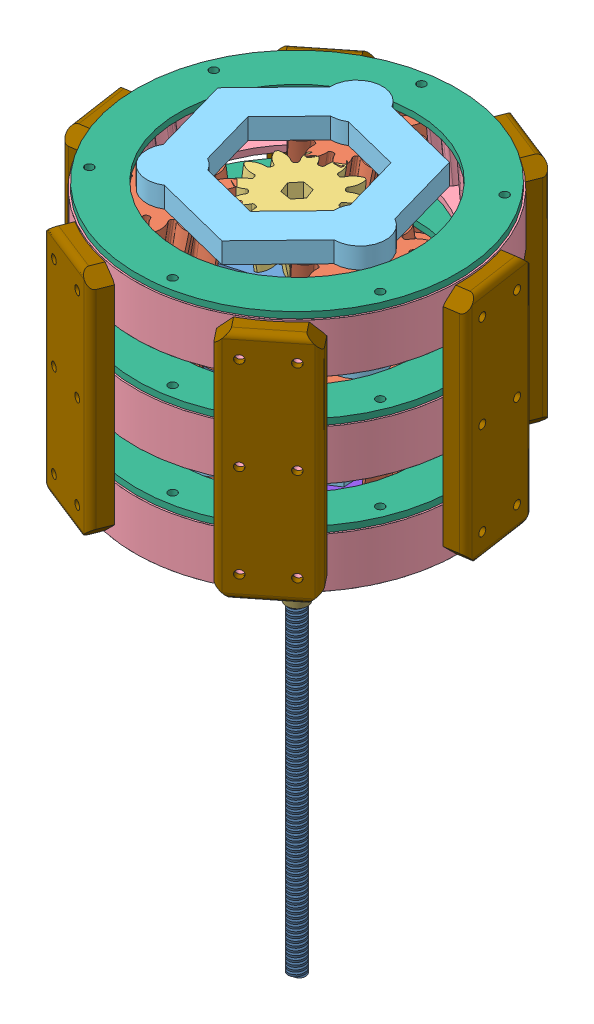
SolidWorks assembly beast_of_burden_REV01, configuration Default. Lengths in mm.
Overall size (217.77 339.35 217.77).
35 component instances, 12 part files, 99 mates.
Components (placement in the parent):
- Planet Carrier REV01-1: Planet Carrier REV01 [Default] at (53.0057 38.5104 215.4418) x (-0.244103 0 0.969749) z (0 1 0) size (94.36 84.54 31)
- planet_helical-1: planet_helical [Default] at (94.0814 53.5104 225.7812) x (-0.940132 0 -0.34081) z (0.34081 0 -0.940132) size (48.42 20.01 48.73)
- sun_helical-1: sun_helical [Default] at (53.0057 53.5104 215.4418) x (-0.935386 0 0.353629) z (-0.353629 0 -0.935386) size (48.42 20.01 48.73)
- planet_helical-2: planet_helical [Default] at (41.4221 53.5104 174.6994) x (-0.765305 0 0.643668) z (-0.643668 0 -0.765305) size (48.42 20.01 48.73)
- planet_helical-3: planet_helical [Default] at (23.5136 53.5104 245.8446) x (0.175396 0 0.984498) z (-0.984498 0 0.175396) size (48.42 20.01 48.73)
- ring_helical-1: ring_helical [Default] at (53.0057 54.0104 215.4418) x (0.989106 0 -0.147208) z (0.147208 0 0.989106) size (166.59 24 159.27)
- Planet Cap REV01-1: Planet Cap REV01 [Default] at (52.6138 69.5104 215.3431) x (-0.717776 0 -0.696274) z (0 1 0) size (98.36 107.21 19)
- ring_helical_cap-1: ring_helical_cap [Default] at (53.0057 64.5104 215.4418) x (0.989106 0 -0.147208) z (0.147208 0 0.989106) size (155 3 155)
- Hand Crank Key REV01-2: Hand Crank Key REV01 [Default] at (53.0057 18.5104 215.4418) x (0.717776 0 0.696274) z (0.696274 0 -0.717776) size (18.48 27 16)
- sun_helical-2: sun_helical [Default] at (53.0057 8.5104 215.4418) x (-0.969749 0 -0.244103) z (0.244103 0 -0.969749) size (48.42 20.01 48.73)
- Planet Carrier REV01-2: Planet Carrier REV01 [Default] at (53.0057 -6.4896 215.4418) x (-0.696169 0 -0.717878) z (0 1 0) size (94.36 84.54 31)
- planet_helical-4: planet_helical [Default] at (42.6723 8.5104 174.3646) x (0.408652 0 0.91269) z (-0.91269 0 0.408652) size (48.42 20.01 48.73)
- planet_helical-5: planet_helical [Default] at (22.5986 8.5104 244.9294) x (0.811958 0 0.583716) z (-0.583716 0 0.811958) size (48.42 20.01 48.73)
- planet_helical-6: planet_helical [Default] at (93.7463 8.5104 227.0313) x (0.41289 0 0.910781) z (-0.910781 0 0.41289) size (48.42 20.01 48.73)
- Planet Cap REV01-2: Planet Cap REV01 [Default] at (53.0057 24.5104 215.4418) x (0.969785 0 -0.243961) z (0 1 0) size (98.36 107.21 19)
- ring_helical-2: ring_helical [Default] at (53.0057 9.0104 215.4418) x (-0.989106 0 0.147208) z (-0.147208 0 -0.989106) size (166.59 24 159.27)
- ring_helical_cap-2: ring_helical_cap [Default] at (53.0057 19.5104 215.4418) x (-0.989106 0 0.147208) z (-0.147208 0 -0.989106) size (155 3 155)
- Hand Crank Key REV01-3: Hand Crank Key REV01 [Default] at (53.0057 -26.4896 215.4418) x (-0.696169 0 -0.717878) z (-0.717878 0 0.696169) size (18.48 27 16)
- sun_helical-3: sun_helical [Default] at (53.0057 -36.4896 215.4418) x (0.243961 0 0.969785) z (-0.969785 0 0.243961) size (48.42 20.01 48.73)
- Planet Cap REV01-3: Planet Cap REV01 [Default] at (53.0057 -20.4896 215.4418) x (0.457092 0 -0.88942) z (0 1 0) size (98.36 107.21 19)
- planet_helical-7: planet_helical [Default] at (88.6095 -36.4896 192.4964) x (0.219463 0 0.975621) z (-0.975621 0 0.219463) size (48.42 20.01 48.73)
- planet_helical-8: planet_helical [Default] at (55.0751 -36.4896 257.7482) x (0.223022 0 0.974813) z (-0.974813 0 0.223022) size (48.42 20.01 48.73)
- planet_helical-9: planet_helical [Default] at (15.3326 -36.4896 196.0807) x (0.675249 0 0.737589) z (-0.737589 0 0.675249) size (48.42 20.01 48.73)
- ring_helical-3: ring_helical [Default] at (53.0057 -35.9896 215.4418) x (0.989106 0 -0.147208) z (0.147208 0 0.989106) size (166.59 24 159.27)
- ring_helical_cap-3: ring_helical_cap [Default] at (53.0057 -25.4896 215.4418) x (0.622038 0 0.782987) z (-0.782987 0 0.622038) size (155 3 155)
- carrier_end_effector_REV01-1: carrier_end_effector_REV01 [Default] at (53.0057 -51.4896 215.4418) x (-0.998806 0 0.048857) z (0 1 0) size (94.36 84.54 41)
- gearbox_spline_REV01-3: gearbox_spline_REV01 [Default] at (53.006 7.5104 215.4422) x (0.622038 0 0.782987) z (-0.782987 0 0.622038) size (10 112.5 38)
- gearbox_spline_REV01-4: gearbox_spline_REV01 [Default] at (53.0054 7.5104 215.4414) x (-0.622038 0 -0.782987) z (0.782987 0 -0.622038) size (10 112.5 38)
- gearbox_spline_REV01-5: gearbox_spline_REV01 [Default] at (53.0055 7.5104 215.4422) x (-0.367067 0 0.930194) z (-0.930194 0 -0.367067) size (10 112.5 38)
- gearbox_spline_REV01-6: gearbox_spline_REV01 [Default] at (53.0052 7.5104 215.4418) x (-0.989106 0 0.147208) z (-0.147208 0 -0.989106) size (10 112.5 38)
- gearbox_spline_REV01-7: gearbox_spline_REV01 [Default] at (53.0059 7.5104 215.4413) x (0.367067 0 -0.930194) z (0.930194 0 0.367067) size (10 112.5 38)
- gearbox_spline_REV01-8: gearbox_spline_REV01 [Default] at (53.0062 7.5104 215.4417) x (0.989106 0 -0.147208) z (0.147208 0 0.989106) size (10 112.5 38)
- LeadScrew 8mm x 2mmPitch-1: LeadScrew 8mm x 2mmPitch [Default] at (53.0057 -263.9896 215.4418) x (0.462821 0 0.886452) z (0 -1 0) size (9.24 8.22 201.1)
- NEMA17_Coupler-1: NEMA17_Coupler [Default] at (53.0057 -56.4896 215.4418) x (0.998806 0 -0.048857) z (-0.048857 0 -0.998806) size (20 26 20)
- LeadScrew Nut 8mm x 2mmPitch-1: LeadScrew Nut 8mm x 2mmPitch [Default] at (53.0057 -94.6476 215.4418) x (0.981052 0 -0.193746) z (0 1 0) size (22 22 16.05)
Mates (geometry in assembly coordinates):
- Concentric1: concentric anti-aligned: cylinder of Planet Carrier REV01-1 through (23.5136 64.5104 245.8446) axis (0 -1 0) radius 9.75; cylinder of planet_helical-3 through (23.5136 43.5061 245.8446) axis (0 1 0) radius 10.1
- Coincident1: coincident anti-aligned: plane of Planet Carrier REV01-1 through (53.0057 43.5104 215.4418) normal (0 1 0); plane of planet_helical-3 through (23.5136 43.5104 245.8446) normal (0 -1 0)
- Concentric2: concentric anti-aligned: cylinder of Planet Carrier REV01-1 through (53.0057 84.0165 215.4418) axis (0 -1 0) radius 7.25; cylinder of sun_helical-1 through (53.0057 43.5061 215.4418) axis (0 1 0) radius 7.6
- Coincident2: coincident anti-aligned: plane of Planet Carrier REV01-1 through (53.0057 43.5104 215.4418) normal (0 1 0); plane of sun_helical-1 through (53.0057 43.5104 215.4418) normal (0 -1 0)
- Concentric3: concentric anti-aligned: cylinder of Planet Carrier REV01-1 through (94.0814 64.5104 225.7812) axis (0 -1 0) radius 9.75; cylinder of planet_helical-1 through (94.0814 43.5061 225.7812) axis (0 1 0) radius 10.1
- Coincident3: coincident anti-aligned: plane of Planet Carrier REV01-1 through (53.0057 43.5104 215.4418) normal (0 1 0); plane of planet_helical-1 through (94.0814 43.5104 225.7812) normal (0 -1 0)
- Concentric4: concentric anti-aligned: cylinder of Planet Carrier REV01-1 through (41.4221 64.5104 174.6994) axis (0 -1 0) radius 9.75; cylinder of planet_helical-2 through (41.4221 43.5061 174.6994) axis (0 1 0) radius 10.1
- Coincident4: coincident anti-aligned: plane of Planet Carrier REV01-1 through (53.0057 43.5104 215.4418) normal (0 1 0); plane of planet_helical-2 through (41.4221 43.5104 174.6994) normal (0 -1 0)
- Concentric9: concentric anti-aligned: cylinder of sun_helical-1 through (53.0057 43.5061 215.4418) axis (0 1 0) radius 7.6; cylinder of ring_helical-1 through (53.0057 64.5104 215.4418) axis (0 -1 0) radius 78.2955
- Coincident5: coincident anti-aligned: plane of planet_helical-2 through (41.4221 43.5104 174.6994) normal (0 -1 0); plane of ring_helical-1 through (53.0057 43.5104 215.4418) normal (0 1 0)
- Parallel4: parallel anti-aligned: plane of Planet Carrier REV01-1 through (98.1013 54.5104 221.6372) normal (-0.244103 0 0.969749); plane of Planet Cap REV01-1 through (92.2211 55.5104 220.5179) normal (0.244103 0 -0.969749)
- Coincident9: coincident anti-aligned: plane of Planet Carrier REV01-1 through (39.8432 54.5104 169.146) normal (0.717776 0 0.696274); plane of Planet Cap REV01-1 through (35.8233 55.5104 173.2901) normal (-0.717776 0 -0.696274)
- Coincident10: coincident anti-aligned: plane of Planet Carrier REV01-1 through (17.9148 54.5104 244.4353) normal (0.961879 0 -0.273475); plane of Planet Cap REV01-1 through (19.3832 55.5104 249.5999) normal (-0.961879 0 0.273475)
- Coincident11: coincident anti-aligned: plane of Planet Carrier REV01-1 through (23.5136 64.5104 245.8446) normal (0 1 0); plane of Planet Cap REV01-1 through (52.6138 64.5104 215.3431) normal (0 -1 0)
- Concentric14: concentric anti-aligned: cylinder of ring_helical-1 through (-2.9778 44.5104 259.9175) axis (0 1 0) radius 2; cylinder of ring_helical_cap-1 through (-2.9778 67.5104 259.9175) axis (0 -1 0) radius 2
- Concentric15: concentric anti-aligned: cylinder of ring_helical-1 through (108.9893 44.5104 170.966) axis (0 1 0) radius 2; cylinder of ring_helical_cap-1 through (108.9893 67.5104 170.966) axis (0 -1 0) radius 2
- Coincident14: coincident anti-aligned: plane of ring_helical-1 through (53.0057 64.5104 215.4418) normal (0 1 0); plane of ring_helical_cap-1 through (53.0057 64.5104 215.4418) normal (0 -1 0)
- GearMate1: gear = 12 : 12 mm: cylinder of planet_helical-2 through (41.4221 43.5061 174.6994) axis (0 1 0) radius 10.1; cylinder of sun_helical-1 through (53.0057 43.5061 215.4418) axis (0 1 0) radius 7.6
- GearMate2: gear = 12 : 12 mm: cylinder of planet_helical-1 through (94.0814 43.5061 225.7812) axis (0 1 0) radius 10.1; cylinder of sun_helical-1 through (53.0057 43.5061 215.4418) axis (0 1 0) radius 7.6
- GearMate3: gear = 12 : 12 mm: cylinder of sun_helical-1 through (53.0057 43.5061 215.4418) axis (0 1 0) radius 7.6; cylinder of planet_helical-3 through (23.5136 43.5061 245.8446) axis (0 1 0) radius 10.1
- GearMate4: gear = 36 : 12 mm: cylinder of planet_helical-1 through (94.0814 43.5061 225.7812) axis (0 1 0) radius 10.1; cylinder of ring_helical-1 through (53.0057 64.5104 215.4418) axis (0 -1 0) radius 78.2955
- Concentric16: concentric aligned: cylinder of Planet Carrier REV01-1 through (53.0057 78.7005 215.4418) axis (0 -1 0) radius 12.4416; cylinder of Hand Crank Key REV01-2 through (53.0057 33.5104 215.4418) axis (0 -1 0) radius 8
- Parallel5: parallel anti-aligned: plane of Planet Carrier REV01-1 through (55.2959 37.7104 206.3436) normal (-0.696274 0 0.717776); plane of Hand Crank Key REV01-2 through (61.8912 37.5104 212.9155) normal (0.696274 0 -0.717776)
- Distance1: distance = 0.2 mm anti-aligned: plane of Planet Carrier REV01-1 through (53.0057 37.7104 215.4418) normal (0 -1 0); plane of Hand Crank Key REV01-2 through (53.0057 37.5104 215.4418) normal (0 1 0)
- Concentric17: concentric anti-aligned: cylinder of Hand Crank Key REV01-2 through (53.0057 33.5104 215.4418) axis (0 -1 0) radius 8; cylinder of sun_helical-2 through (53.0057 -1.4939 215.4418) axis (0 1 0) radius 7.6
- Coincident20: coincident anti-aligned: plane of Hand Crank Key REV01-2 through (53.0057 18.5104 215.4418) normal (0 -1 0); plane of sun_helical-2 through (53.0057 18.5104 215.4418) normal (0 1 0)
- Parallel6: parallel anti-aligned: plane of Hand Crank Key REV01-2 through (51.681 10.5104 220.7047) normal (-0.696274 0 0.717776); plane of sun_helical-2 through (47.6467 -25.8141 216.9654) normal (0.696274 0 -0.717776)
- Concentric18: concentric anti-aligned: cylinder of sun_helical-2 through (53.0057 -1.4939 215.4418) axis (0 1 0) radius 7.6; cylinder of Planet Carrier REV01-2 through (53.0057 39.0165 215.4418) axis (0 -1 0) radius 7.25
- Coincident23: coincident anti-aligned: plane of sun_helical-2 through (53.0057 -1.4896 215.4418) normal (0 -1 0); plane of Planet Carrier REV01-2 through (53.0057 -1.4896 215.4418) normal (0 1 0)
- Concentric19: concentric anti-aligned: cylinder of Planet Carrier REV01-2 through (42.6723 19.5104 174.3646) axis (0 -1 0) radius 9.75; cylinder of planet_helical-4 through (42.6723 -1.4939 174.3646) axis (0 1 0) radius 10.1
- Coincident24: coincident anti-aligned: plane of Planet Carrier REV01-2 through (53.0057 -1.4896 215.4418) normal (0 1 0); plane of planet_helical-4 through (42.6723 -1.4896 174.3646) normal (0 -1 0)
- GearMate5: gear = 12 : 12 mm: cylinder of planet_helical-4 through (42.6723 -1.4939 174.3646) axis (0 1 0) radius 10.1; cylinder of sun_helical-2 through (53.0057 -1.4939 215.4418) axis (0 1 0) radius 7.6
- Concentric20: concentric anti-aligned: cylinder of Planet Carrier REV01-2 through (22.5986 19.5104 244.9294) axis (0 -1 0) radius 9.75; cylinder of planet_helical-5 through (22.5986 -1.4939 244.9294) axis (0 1 0) radius 10.1
- Coincident25: coincident anti-aligned: plane of Planet Carrier REV01-2 through (53.0057 -1.4896 215.4418) normal (0 1 0); plane of planet_helical-5 through (22.5986 -1.4896 244.9294) normal (0 -1 0)
- GearMate6: gear = 12 : 12 mm: cylinder of planet_helical-5 through (22.5986 -1.4939 244.9294) axis (0 1 0) radius 10.1; cylinder of sun_helical-2 through (53.0057 -1.4939 215.4418) axis (0 1 0) radius 7.6
- Concentric22: concentric anti-aligned: cylinder of Planet Carrier REV01-2 through (93.7463 19.5104 227.0313) axis (0 -1 0) radius 9.75; circle of planet_helical-6
- Coincident26: coincident anti-aligned: plane of Planet Carrier REV01-2 through (53.0057 -1.4896 215.4418) normal (0 1 0); plane of planet_helical-6 through (93.7463 -1.4896 227.0313) normal (0 -1 0)
- GearMate7: gear = 12 : 12 mm: cylinder of planet_helical-6 through (93.7463 -1.4939 227.0313) axis (0 1 0) radius 10.1; cylinder of sun_helical-2 through (53.0057 -1.4939 215.4418) axis (0 1 0) radius 7.6
- Concentric24: concentric aligned: cylinder of Planet Carrier REV01-2 through (93.7463 -1.4896 227.0313) axis (0 -1 0) radius 10.5; cylinder of Planet Cap REV01-2 through (93.7463 29.5104 227.0313) axis (0 -1 0) radius 12.5
- Concentric25: concentric aligned: cylinder of Planet Carrier REV01-2 through (22.5986 -1.4896 244.9294) axis (0 -1 0) radius 10.5; cylinder of Planet Cap REV01-2 through (22.5986 29.5104 244.9294) axis (0 -1 0) radius 12.5
- Coincident27: coincident anti-aligned: plane of Planet Carrier REV01-2 through (22.5986 19.5104 244.9294) normal (0 1 0); plane of Planet Cap REV01-2 through (53.0057 19.5104 215.4418) normal (0 -1 0)
- Coincident29: coincident anti-aligned: plane of planet_helical-6 through (93.7463 -1.4896 227.0313) normal (0 -1 0); plane of ring_helical-2 through (53.0057 -1.4896 215.4418) normal (0 1 0)
- GearMate8: gear = 36 : 36 mm: cylinder of planet_helical-6 through (93.7463 -1.4939 227.0313) axis (0 1 0) radius 10.1; cylinder of ring_helical-2 through (53.0057 19.5104 215.4418) axis (0 -1 0) radius 78.2955
- Concentric28: concentric anti-aligned: cylinder of ring_helical-2 through (119.5146 -0.4896 241.6871) axis (0 1 0) radius 2; cylinder of ring_helical_cap-2 through (119.5146 22.5104 241.6871) axis (0 -1 0) radius 2
- Concentric29: concentric anti-aligned: cylinder of ring_helical-2 through (-13.5032 -0.4896 189.1964) axis (0 1 0) radius 2; cylinder of ring_helical_cap-2 through (-13.5032 22.5104 189.1964) axis (0 -1 0) radius 2
- Coincident30: coincident anti-aligned: plane of ring_helical-2 through (53.0057 19.5104 215.4418) normal (0 1 0); plane of ring_helical_cap-2 through (53.0057 19.5104 215.4418) normal (0 -1 0)
- Concentric30: concentric aligned: cylinder of Planet Carrier REV01-2 through (53.0057 33.7005 215.4418) axis (0 -1 0) radius 12.4416; cylinder of Hand Crank Key REV01-3 through (53.0057 -11.4896 215.4418) axis (0 -1 0) radius 8
- Parallel10: parallel anti-aligned: plane of Planet Carrier REV01-2 through (55.5728 -7.2896 206.4178) normal (-0.717878 0 0.696169); plane of Hand Crank Key REV01-3 through (61.9642 -7.4896 213.1881) normal (0.717878 0 -0.696169)
- Distance2: distance = 0.2 mm anti-aligned: plane of Planet Carrier REV01-2 through (53.0057 -7.2896 215.4418) normal (0 -1 0); plane of Hand Crank Key REV01-3 through (53.0057 -7.4896 215.4418) normal (0 1 0)
- Concentric31: concentric anti-aligned: cylinder of Hand Crank Key REV01-3 through (53.0057 -11.4896 215.4418) axis (0 -1 0) radius 8; cylinder of sun_helical-3 through (53.0057 -46.4939 215.4418) axis (0 1 0) radius 7.6
- Parallel11: parallel anti-aligned: plane of Hand Crank Key REV01-3 through (58.2688 -34.4896 214.1178) normal (0.961839 0 0.273616); plane of sun_helical-3 through (56.8844 -70.8141 219.4414) normal (-0.961839 0 -0.273616)
- Coincident34: coincident anti-aligned: plane of Hand Crank Key REV01-3 through (53.0057 -26.4896 215.4418) normal (0 -1 0); plane of sun_helical-3 through (53.0057 -26.4896 215.4418) normal (0 1 0)
- GearMate9: gear = 12 : 12 mm: cylinder of planet_helical-9 through (15.3326 -46.4939 196.0807) axis (0 1 0) radius 10.1; cylinder of sun_helical-3 through (53.0057 -46.4939 215.4418) axis (0 1 0) radius 7.6
- GearMate10: gear = 12 : 12 mm: cylinder of planet_helical-8 through (55.0751 -46.4939 257.7482) axis (0 1 0) radius 10.1; cylinder of sun_helical-3 through (53.0057 -46.4939 215.4418) axis (0 1 0) radius 7.6
- GearMate11: gear = 12 : 12 mm: cylinder of sun_helical-3 through (53.0057 -46.4939 215.4418) axis (0 1 0) radius 7.6; cylinder of planet_helical-7 through (88.6095 -46.4939 192.4964) axis (0 1 0) radius 10.1
- Concentric39: concentric aligned: cylinder of ring_helical-1 through (53.0057 64.5104 215.4418) axis (0 -1 0) radius 78.2955; cylinder of ring_helical-3 through (53.0057 -25.4896 215.4418) axis (0 -1 0) radius 78.2955
- Coincident40: coincident aligned: plane of ring_helical-1 through (113.4316 56.0104 273.8186) normal (0.622038 0 0.782987); plane of ring_helical-3 through (113.4316 -33.9896 273.8186) normal (0.622038 0 0.782987)
- Coincident41: coincident anti-aligned: plane of planet_helical-7 through (88.6095 -46.4896 192.4964) normal (0 -1 0); plane of ring_helical-3 through (53.0057 -46.4896 215.4418) normal (0 1 0)
- GearMate12: gear = 12 : 36 mm: cylinder of ring_helical-3 through (53.0057 -25.4896 215.4418) axis (0 -1 0) radius 78.2955; cylinder of planet_helical-9 through (15.3326 -46.4939 196.0807) axis (0 1 0) radius 10.1
- Concentric41: concentric anti-aligned: cylinder of ring_helical-3 through (42.4804 -45.4896 144.7207) axis (0 1 0) radius 2; cylinder of ring_helical_cap-3 through (42.4804 -22.4896 144.7207) axis (0 -1 0) radius 2
- Concentric44: concentric anti-aligned: cylinder of ring_helical-3 through (119.5146 -45.4896 241.6871) axis (0 1 0) radius 2; cylinder of ring_helical_cap-3 through (119.5146 -22.4896 241.6871) axis (0 -1 0) radius 2
- Coincident43: coincident anti-aligned: plane of ring_helical-3 through (53.0057 -25.4896 215.4418) normal (0 1 0); plane of ring_helical_cap-3 through (53.0057 -25.4896 215.4418) normal (0 -1 0)
- Concentric45: concentric anti-aligned: cylinder of planet_helical-8 through (55.0751 -46.4939 257.7482) axis (0 1 0) radius 10.1; cylinder of carrier_end_effector_REV01-1 through (55.0751 -25.4896 257.7482) axis (0 -1 0) radius 9.75
- Concentric47: concentric aligned: cylinder of Planet Cap REV01-3 through (55.0751 -15.4896 257.7482) axis (0 -1 0) radius 12.5; cylinder of carrier_end_effector_REV01-1 through (55.0751 -46.4896 257.7482) axis (0 -1 0) radius 10.5
- Coincident44: coincident anti-aligned: plane of Planet Cap REV01-3 through (53.0057 -25.4896 215.4418) normal (0 -1 0); plane of carrier_end_effector_REV01-1 through (55.0751 -25.4896 257.7482) normal (0 1 0)
- Concentric48: concentric aligned: cylinder of Planet Cap REV01-3 through (15.3326 -15.4896 196.0807) axis (0 -1 0) radius 12.5; cylinder of carrier_end_effector_REV01-1 through (15.3326 -46.4896 196.0807) axis (0 -1 0) radius 10.5
- Concentric49: concentric anti-aligned: cylinder of planet_helical-9 through (15.3326 -46.4939 196.0807) axis (0 1 0) radius 10.1; cylinder of carrier_end_effector_REV01-1 through (15.3326 -25.4896 196.0807) axis (0 -1 0) radius 9.75
- Concentric50: concentric anti-aligned: cylinder of planet_helical-7 through (88.6095 -46.4939 192.4964) axis (0 1 0) radius 10.1; cylinder of carrier_end_effector_REV01-1 through (88.6095 -25.4896 192.4964) axis (0 -1 0) radius 9.75
- Concentric51: concentric anti-aligned: cylinder of sun_helical-3 through (53.0057 -46.4939 215.4418) axis (0 1 0) radius 7.6; cylinder of carrier_end_effector_REV01-1 through (53.0057 -5.9835 215.4418) axis (0 -1 0) radius 7.25
- Coincident45: coincident anti-aligned: plane of planet_helical-7 through (88.6095 -46.4896 192.4964) normal (0 -1 0); plane of carrier_end_effector_REV01-1 through (53.0057 -46.4896 215.4418) normal (0 1 0)
- Coincident46: coincident anti-aligned: plane of planet_helical-8 through (55.0751 -46.4896 257.7482) normal (0 -1 0); plane of carrier_end_effector_REV01-1 through (53.0057 -46.4896 215.4418) normal (0 1 0)
- Coincident47: coincident anti-aligned: plane of planet_helical-9 through (15.3326 -46.4896 196.0807) normal (0 -1 0); plane of carrier_end_effector_REV01-1 through (53.0057 -46.4896 215.4418) normal (0 1 0)
- Coincident48: coincident anti-aligned: plane of sun_helical-3 through (53.0057 -46.4896 215.4418) normal (0 -1 0); plane of carrier_end_effector_REV01-1 through (53.0057 -46.4896 215.4418) normal (0 1 0)
- Concentric52: concentric anti-aligned: cylinder of carrier_end_effector_REV01-1 through (53.0057 -56.4896 215.4418) axis (0 -1 0) radius 10.15; cylinder of NEMA17_Coupler-1 through (53.0057 -56.4896 215.4418) axis (0 1 0) radius 10
- Concentric53: concentric anti-aligned: cylinder of carrier_end_effector_REV01-1 through (51.458 -61.4896 183.8011) axis (0.048857 0 0.998806) radius 1.65; cylinder of NEMA17_Coupler-1 through (52.5172 -61.4896 205.4537) axis (-0.048857 0 -0.998806) radius 1.65
- Concentric54: concentric aligned: cylinder of NEMA17_Coupler-1 through (53.0057 -56.4896 215.4418) axis (0 1 0) radius 4.025; circle of LeadScrew 8mm x 2mmPitch-1
- Coincident49: coincident anti-aligned: plane of NEMA17_Coupler-1 through (56.7762 -63.9896 215.2573) normal (0 -1 0); plane of LeadScrew 8mm x 2mmPitch-1 through (53.0057 -63.9896 215.4418) normal (0 1 0)
- Concentric68: concentric aligned: cylinder of ring_helical-1 through (53.0057 64.5104 215.4418) axis (0 -1 0) radius 78.2955; cylinder of ring_helical-2 through (53.0057 19.5104 215.4418) axis (0 -1 0) radius 78.2955
- Coincident54: coincident aligned: plane of ring_helical-1 through (113.4316 56.0104 273.8186) normal (0.622038 0 0.782987); plane of ring_helical-2 through (113.4316 11.0104 273.8186) normal (0.622038 0 0.782987)
- Concentric69: concentric anti-aligned: cylinder of ring_helical-1 through (92.6346 52.5104 281.4005) axis (0.622038 0 0.782987) radius 2; cylinder of gearbox_spline_REV01-3 through (98.855 52.5104 289.2304) axis (-0.622038 0 -0.782987) radius 2
- Coincident55: coincident anti-aligned: plane of ring_helical-1 through (113.4316 56.0104 273.8186) normal (0.622038 0 0.782987); plane of gearbox_spline_REV01-3 through (96.0884 56.1604 287.5968) normal (-0.622038 0 -0.782987)
- Concentric70: concentric anti-aligned: cylinder of ring_helical-1 through (108.2943 52.5104 268.9597) axis (0.622038 0 0.782987) radius 2; cylinder of gearbox_spline_REV01-3 through (114.5147 52.5104 276.7896) axis (-0.622038 0 -0.782987) radius 2
- Concentric71: concentric anti-aligned: cylinder of ring_helical-1 through (13.3769 52.5104 149.483) axis (-0.622038 0 -0.782987) radius 2; cylinder of gearbox_spline_REV01-4 through (7.1565 52.5104 141.6531) axis (0.622038 0 0.782987) radius 2
- Concentric72: concentric anti-aligned: cylinder of ring_helical-1 through (-2.2829 52.5104 161.9238) axis (-0.622038 0 -0.782987) radius 2; cylinder of gearbox_spline_REV01-4 through (-8.5032 52.5104 154.0939) axis (0.622038 0 0.782987) radius 2
- Coincident56: coincident anti-aligned: plane of ring_helical-1 through (-7.4201 56.0104 157.0649) normal (-0.622038 0 -0.782987); plane of gearbox_spline_REV01-4 through (9.923 56.1604 143.2868) normal (0.622038 0 0.782987)
- Concentric73: concentric anti-aligned: cylinder of ring_helical-1 through (126.998 52.5104 194.3194) axis (0.989106 0 -0.147208) radius 2; cylinder of gearbox_spline_REV01-8 through (136.889 52.5104 192.8474) axis (-0.989106 0 0.147208) radius 2
- Concentric74: concentric anti-aligned: cylinder of ring_helical-1 through (129.9421 52.5104 214.1015) axis (0.989106 0 -0.147208) radius 2; cylinder of gearbox_spline_REV01-8 through (139.8332 52.5104 212.6295) axis (-0.989106 0 0.147208) radius 2
- Coincident57: coincident anti-aligned: plane of ring_helical-1 through (133.7745 56.0104 192.2999) normal (0.989106 0 -0.147208); plane of gearbox_spline_REV01-8 through (137.0351 56.1604 214.2086) normal (-0.989106 0 0.147208)
- Concentric75: concentric anti-aligned: cylinder of ring_helical-1 through (-23.9307 52.5104 216.782) axis (-0.989106 0 0.147208) radius 2; cylinder of gearbox_spline_REV01-6 through (-33.8217 52.5104 218.2541) axis (0.989106 0 -0.147208) radius 2
- Concentric76: concentric anti-aligned: cylinder of ring_helical-1 through (-20.9865 52.5104 236.5641) axis (-0.989106 0 0.147208) radius 2; cylinder of gearbox_spline_REV01-6 through (-30.8776 52.5104 238.0362) axis (0.989106 0 -0.147208) radius 2
- Coincident58: coincident anti-aligned: plane of ring_helical-1 through (-27.763 56.0104 238.5837) normal (-0.989106 0 0.147208); plane of gearbox_spline_REV01-6 through (-31.0237 56.1604 216.675) normal (0.989106 0 -0.147208)
- Concentric77: concentric anti-aligned: cylinder of ring_helical-1 through (15.6982 52.5104 282.7407) axis (-0.367067 0 0.930194) radius 2; cylinder of gearbox_spline_REV01-5 through (12.0275 52.5104 292.0427) axis (0.367067 0 -0.930194) radius 2
- Concentric78: concentric anti-aligned: cylinder of ring_helical-1 through (34.3021 52.5104 290.0821) axis (-0.367067 0 0.930194) radius 2; cylinder of gearbox_spline_REV01-5 through (30.6314 52.5104 299.384) axis (0.367067 0 -0.930194) radius 2
- Coincident59: coincident anti-aligned: plane of ring_helical-1 through (32.6628 56.0104 296.9605) normal (-0.367067 0 0.930194); plane of gearbox_spline_REV01-5 through (12.059 56.1604 288.83) normal (0.367067 0 -0.930194)
- Concentric79: concentric anti-aligned: cylinder of ring_helical-1 through (71.7094 52.5104 140.8014) axis (0.367067 0 -0.930194) radius 2; cylinder of gearbox_spline_REV01-7 through (75.38 52.5104 131.4995) axis (-0.367067 0 0.930194) radius 2
- Concentric80: concentric anti-aligned: cylinder of ring_helical-1 through (90.3133 52.5104 148.1428) axis (0.367067 0 -0.930194) radius 2; cylinder of gearbox_spline_REV01-7 through (93.9839 52.5104 138.8408) axis (-0.367067 0 0.930194) radius 2
- Coincident60: coincident anti-aligned: plane of ring_helical-1 through (73.3486 56.0104 133.923) normal (0.367067 0 -0.930194); plane of gearbox_spline_REV01-7 through (93.9525 56.1604 142.0536) normal (-0.367067 0 0.930194)
- Screw1: screw = 2 mm anti-aligned: line of LeadScrew 8mm x 2mmPitch-1 through (53.0057 -64.1896 215.4418) axis (0 -1 0); cylinder of LeadScrew Nut 8mm x 2mmPitch-1 through (53.0057 -108.1476 215.4418) axis (0 1 0) radius 5.1
- Concentric81: concentric anti-aligned: cylinder of ring_helical_cap-1 through (53.0057 67.5104 215.4418) axis (0 -1 0) radius 77.4975; cylinder of LeadScrew Nut 8mm x 2mmPitch-1 through (53.0057 -98.1476 215.4418) axis (0 1 0) radius 11
